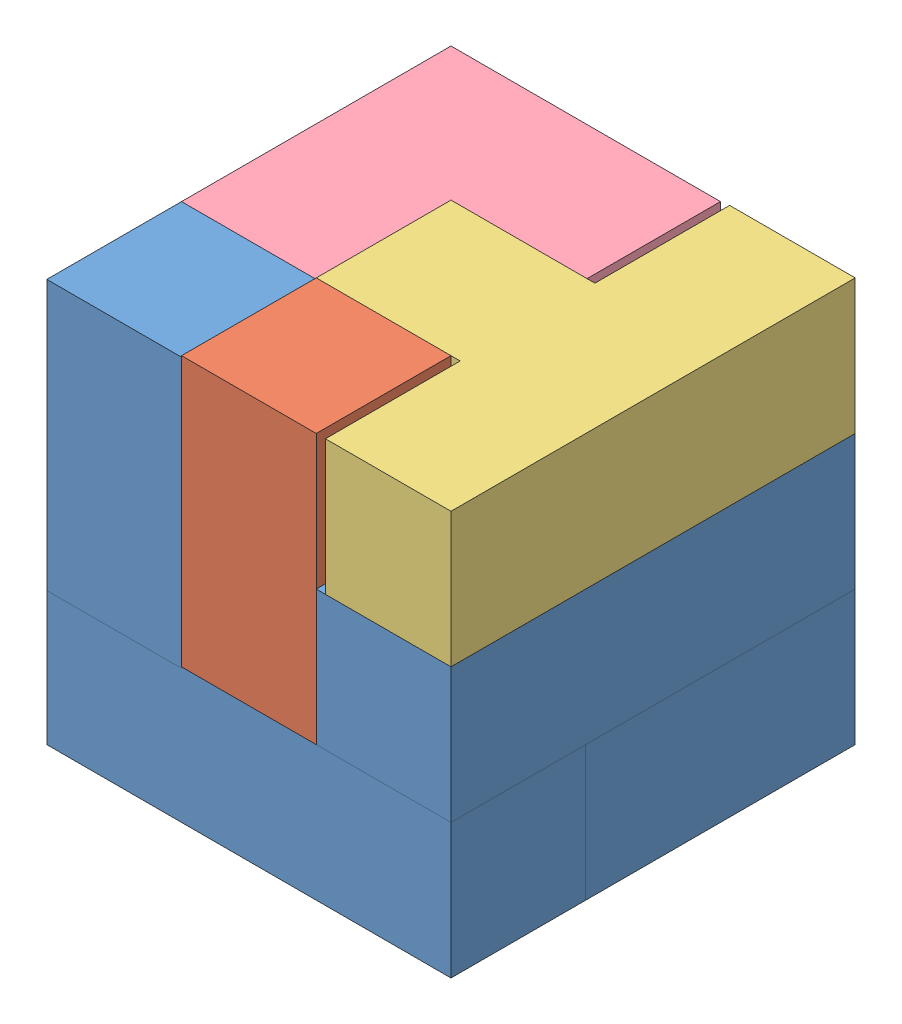
SolidWorks assembly Assem1, configuration Default. Lengths in mm.
Overall size (90 90 90).
7 component instances, 4 part files, 16 mates.
Components (placement in the parent):
- a3-2: a3 [Default] at (-22.3705 42.4805 54.5541) x (1 0 0) z (0 -1 0) size (90 60 30)
- a3-3: a3 [Default] at (67.6295 42.4805 144.5541) x (-1 0 0) z (0 -1 0) size (90 60 30)
- a3-4: a3 [Default] at (7.6295 42.1927 54.5541) x (0 0 1) z (-1 0 0) size (90 60 30)
- a3-5: a3 [Default] at (67.6295 42.4805 144.5541) x (0 0 -1) z (0 1 0) size (90 60 30)
- a4-1: a4 [Default] at (7.6295 102.4805 144.5541) x (0 -1 0) z (1 0 0) size (90 60 30)
- a2-1: a2 [Default] at (67.6295 102.4805 54.5541) x (0 0 1) z (0 -1 0) size (90 60 30)
- a1-1: a1 [Default] at (-22.3705 102.1927 54.5541) x (1 0 0) z (0 -1 0) size (60 60 30)
Mates (geometry in assembly coordinates):
- Coincident7: coincident anti-aligned: plane of a3-2 through (37.6295 12.4805 84.5541) normal (0 0 1); plane of a3-3 through (-22.3705 12.4805 84.5541) normal (0 0 -1)
- Coincident8: coincident aligned: plane of a3-2 through (-22.3705 12.4805 84.5541) normal (-1 0 0); plane of a3-3 through (-22.3705 12.4805 144.5541) normal (-1 0 0)
- Coincident9: coincident aligned: plane of a3-2 through (-22.3705 42.4805 54.5541) normal (0 1 0); plane of a3-3 through (67.6295 42.4805 144.5541) normal (0 1 0)
- Coincident11: coincident anti-aligned: plane of a3-2 through (-22.3705 42.4805 54.5541) normal (0 1 0); plane of a3-5 through (67.6295 42.4805 144.5541) normal (0 -1 0)
- Coincident12: coincident aligned: plane of a3-2 through (67.6295 12.4805 54.5541) normal (1 0 0); plane of a3-5 through (67.6295 72.4805 144.5541) normal (1 0 0)
- Coincident13: coincident aligned: plane of a3-2 through (-22.3705 12.4805 54.5541) normal (0 0 -1); plane of a3-5 through (67.6295 72.4805 54.5541) normal (0 0 -1)
- Coincident14: coincident aligned: plane of a3-2 through (-22.3705 12.4805 54.5541) normal (0 0 -1); plane of a3-4 through (-22.3705 72.1927 54.5541) normal (0 0 -1)
- Coincident15: coincident aligned: plane of a3-3 through (-22.3705 12.4805 144.5541) normal (-1 0 0); plane of a3-4 through (-22.3705 42.1927 54.5541) normal (-1 0 0)
- Coincident17: coincident anti-aligned: plane of a3-5 through (7.6295 72.4805 84.5541) normal (0 0 1); plane of a4-1 through (37.6295 12.4805 84.5541) normal (0 0 -1)
- Coincident18: coincident anti-aligned: plane of a3-5 through (37.6295 72.4805 84.5541) normal (-1 0 0); plane of a4-1 through (37.6295 102.4805 144.5541) normal (1 0 0)
- Coincident19: coincident aligned: plane of a3-3 through (67.6295 12.4805 144.5541) normal (0 -1 0); plane of a4-1 through (37.6295 12.4805 114.5541) normal (0 -1 0)
- Coincident22: coincident aligned: plane of a3-5 through (37.6295 72.4805 144.5541) normal (0 0 1); plane of a2-1 through (67.6295 72.4805 144.5541) normal (0 0 1)
- Coincident26: coincident aligned: plane of a4-1 through (37.6295 102.4805 114.5541) normal (0 1 0); plane of a2-1 through (67.6295 102.4805 54.5541) normal (0 1 0)
- Coincident27: coincident aligned: plane of a3-5 through (67.6295 72.4805 144.5541) normal (1 0 0); plane of a2-1 through (67.6295 72.4805 54.5541) normal (1 0 0)
- Coincident28: coincident anti-aligned: plane of a3-4 through (-22.3705 72.1927 114.5541) normal (0 1 0); plane of a1-1 through (-20.3273 72.1927 54.5541) normal (0 -1 0)
- Coincident30: coincident aligned: plane of a3-4 through (-22.3705 42.1927 54.5541) normal (-1 0 0); plane of a1-1 through (-22.3705 72.1927 54.5541) normal (-1 0 0)
